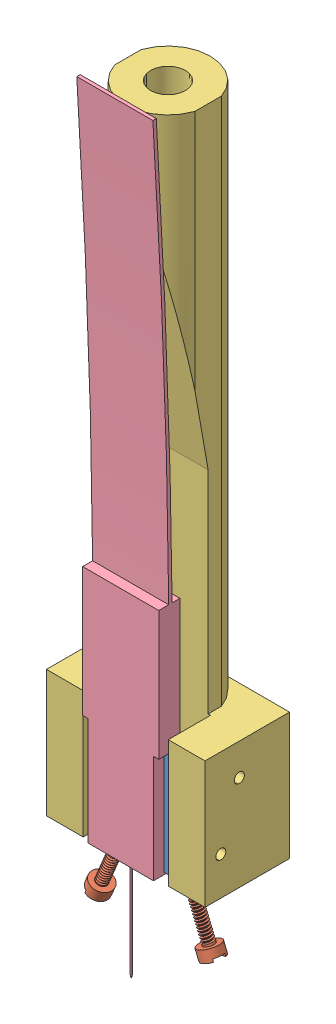
SolidWorks assembly Assem1, configuration Default. Lengths in mm.
Overall size (15 72.83 9.05).
5 component instances, 4 part files, 9 mates.
Components (placement in the parent):
- neuropixel_holder-1: neuropixel_holder [Standard] at (-45.1661 19.9461 11.6436) size (8 10.96 3.5)
- screw-1: screw [Standard] at (-42.3825 13.2976 11.3936) x (-0.382683 -0.92388 0) z (0.647685 -0.26828 0.713113) size (11.14 2 2)
- stereotax_holder-1: stereotax_holder [Standard] at (-41.1911 71.5098 10.1436) x (1 0 0) z (0 -1 0) size (15 8 62)
- screw-3: screw [Standard] at (-39.8661 13.1981 11.3936) x (0.382683 -0.92388 0) z (-0.195556 -0.081002 0.977342) size (11.14 2 2)
- Neuropixel 2019-2: Neuropixel 2019 [Default] at (-41.1661 26.0461 14.6436) x (-1 0 0) z (0 -1 0) size (7.2 2.55 72.83)
Mates (geometry in assembly coordinates):
- Coincident1: coincident: plane of neuropixel_holder-1 through (-45.1661 19.9461 10.1436) normal (0 0 -1); plane of stereotax_holder-1 through (-41.1911 71.5098 10.1436) normal (0 0 1)
- Coincident3: coincident: plane of neuropixel_holder-1 through (-37.1661 19.9461 13.6436) normal (1 0 0); plane of stereotax_holder-1 through (-37.1661 41.5098 10.1436) normal (-1 0 0)
- Screw1: screw = 1: cylinder of neuropixel_holder-1 through (-43.975 9.4528 11.3936) axis (-0.382683 -0.92388 0) radius 0.6; cylinder of screw-1 through (-46.592 3.1349 11.3936) axis (0.382683 0.92388 0) radius 1
- Concentric1: concentric: cylinder of neuropixel_holder-1 through (-38.3209 9.4678 11.3936) axis (0.382683 -0.92388 0) radius 0.5; cylinder of screw-3 through (-35.6566 3.0354 11.3936) axis (-0.382683 0.92388 0) radius 1
- Parallel1: parallel: plane of neuropixel_holder-1 through (-45.1661 19.9461 11.6436) normal (0 0 -1); plane of stereotax_holder-1 through (-41.1911 71.5098 11.6436) normal (0 0 1)
- Coincident5: coincident: plane of neuropixel_holder-1 through (-42.8564 8.9894 12.6436) normal (0.92388 -0.382683 0); plane of stereotax_holder-1 through (-42.6408 9.5098 11.6436) normal (-0.92388 0.382683 0)
- Coincident7: coincident: plane of neuropixel_holder-1 through (-45.1661 19.9461 12.6436) normal (0 0 1); plane of Neuropixel 2019-2 through (-41.1661 26.0461 12.6436) normal (0 0 -1)
- Coincident8: coincident: plane of neuropixel_holder-1 through (-38.0661 19.9461 12.6436) normal (-1 0 0); plane of Neuropixel 2019-2 through (-38.0661 26.0461 12.6436) normal (1 0 0)
- Coincident11: coincident: plane of neuropixel_holder-1 through (-45.1661 19.9461 13.6436) normal (0 1 0); plane of Neuropixel 2019-2 through (-41.1661 19.9461 12.6436) normal (0 -1 0)
